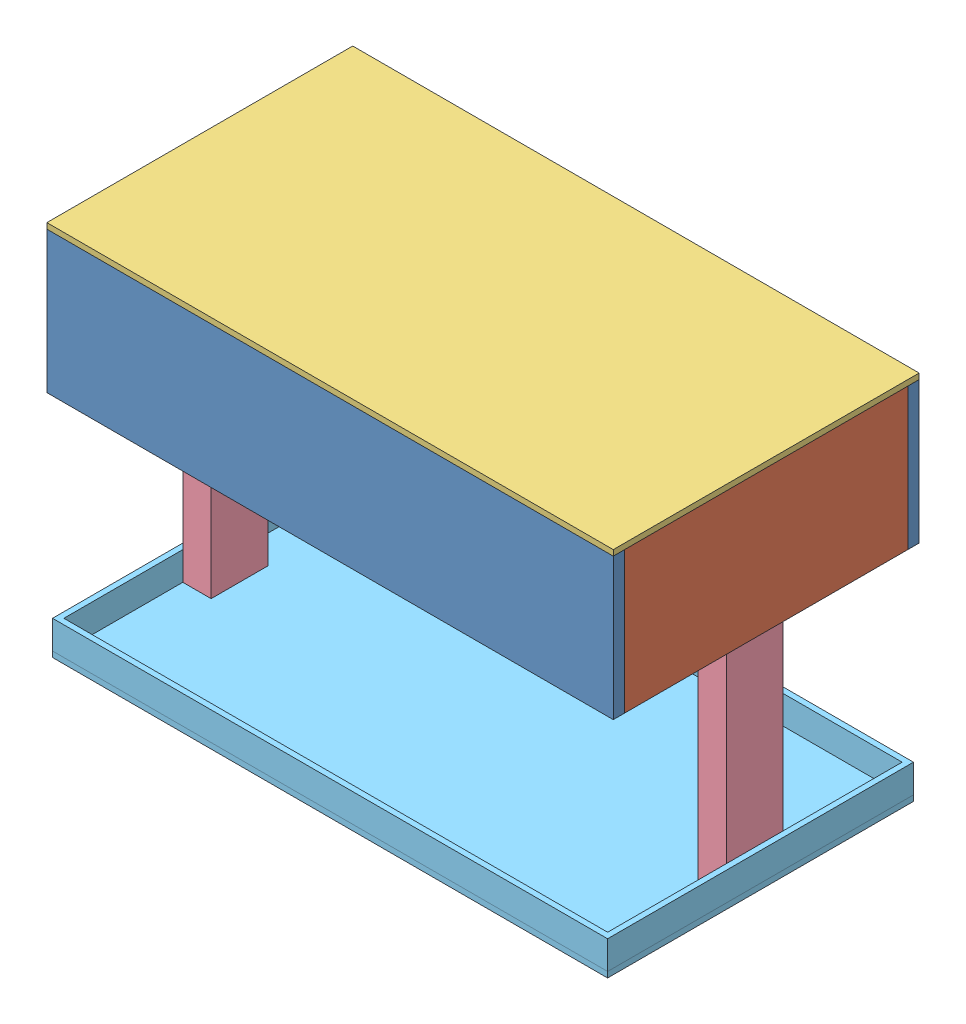
SolidWorks assembly Full_Assembly, configuration Default. Lengths in mm.
Overall size (1000 660 540).
10 component instances, 5 part files, 3 mates.
Components (placement in the parent):
- BottomBasin-1: BottomBasin [Default] at (159.0904 521.0407 881.16) size (1000 260 540)
  - LengthPanel-1: LengthPanel [Default] at (498.2133 647.727 616.1406) size (1000 250 20)
  - LengthPanel-2: LengthPanel [Default] at (498.2133 647.727 1136.1406) size (1000 250 20)
  - Widthpanel-1: Widthpanel [Default] at (998.2133 647.727 886.1406) x (0 0 1) z (-1 0 0) size (500 250 20)
  - Widthpanel-2: Widthpanel [Default] at (-1.7867 647.727 886.1406) x (0 0 -1) z (1 0 0) size (500 250 20)
  - BottomPlate-1: BottomPlate [Default] at (498.2133 772.727 886.1406) size (1000 10 540)
- TopPart-1: TopPart [Default] at (4285.0901 -3657.3186 4339.5681) x (0 0 -1) z (0 1 0) size (540 980 650)
  - Pillars-1: Pillars [Default] at (2572.2675 4082.7865 4311.0862) size (100 50 640)
  - Pillars-2: Pillars [Default] at (2572.2675 3172.7865 4311.0862) size (100 50 640)
  - top part-1: top part [Default] at (2572.2675 3627.7865 4311.0862) x (0 -1 0) z (1 0 0) size (980 60 540)
Mates (geometry in assembly coordinates):
- Coincident1: coincident anti-aligned: plane of BottomBasin-1/BottomPlate-1 through (657.3037 1293.7676 1767.3006) normal (0 -1 0); plane of TopPart-1/Pillars-2 through (1112.3037 1293.7676 1867.3006) normal (0 1 0)
- Coincident2: coincident anti-aligned: plane of BottomBasin-1/Widthpanel-1 through (1137.3037 1168.7676 1767.3006) normal (-1 0 0); plane of TopPart-1/Pillars-2 through (1137.3037 1293.7676 1917.3006) normal (1 0 0)
- Distance2: distance = 200 mm: line of TopPart-1/Pillars-2 through (1137.3037 1293.7676 1717.3006) axis (0 -1 0); point of BottomBasin-1/Widthpanel-1
